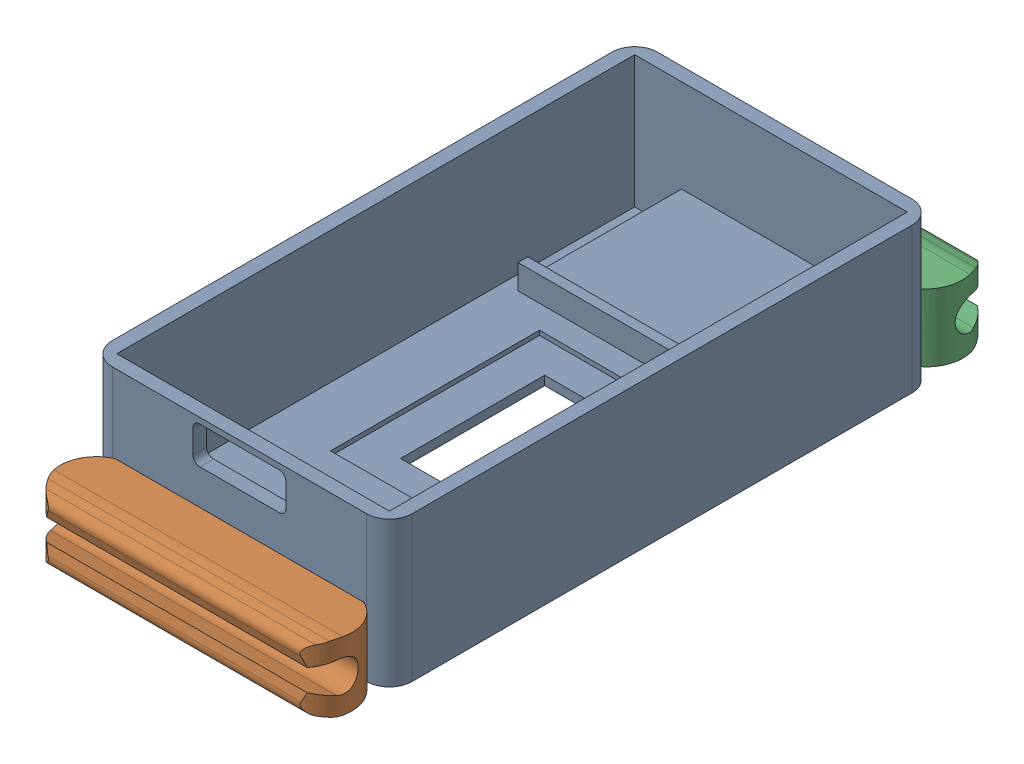
SolidWorks assembly Case Assembly, configuration Default. Lengths in mm.
Overall size (33 16 74.36).
8 component instances, 4 part files, 15 mates.
Components (placement in the parent):
- Case-1: Case [Default] at origin size (33 16 60)
- Apple Watch Band Female Connector-1: Apple Watch Band Female Connector [Default] at (16.9873 3.75 51.3416) x (0 0 -1) z (1 0 0) size (7.18 7.5 32)
- Apple Watch Band Female Connector-2: Apple Watch Band Female Connector [Default] at (16.9784 3.75 -13.864) x (0 0 1) z (-1 0 0) size (7.18 7.5 32)
- Case Top-1: Case Top [Default] at (0 16 -2.6495) (suppressed, hidden)
- Support Beam-2: Support Beam [Default] at (20.7334 64.9364 -6.6469) x (0.999394 0 -0.034819) z (0.034819 0 0.999394) (suppressed, hidden)
- Support Beam-5: Support Beam [Default] at (-3.0213 64.9364 -6.9302) (suppressed, hidden)
- Support Beam-7: Support Beam [Default] at (20.7744 64.9364 43.8698) (suppressed, hidden)
- Support Beam-8: Support Beam [Default] at (-3.0256 64.9364 43.8698) (suppressed, hidden)
Mates (geometry in assembly coordinates):
- Coincident1: coincident anti-aligned: line of Case-1 through (2.9896 0 48.7388) axis (1 0 0); line of Apple Watch Band Female Connector-1 through (30.6627 0 48.7388) axis (-1 0 0)
- Coincident2: coincident anti-aligned: plane of Case-1 through (0.4896 16 48.7388) normal (0 0 1); plane of Apple Watch Band Female Connector-1 through (32.9873 3.75 48.7388) normal (0 0 -1)
- Coincident3: coincident anti-aligned: line of Case-1 through (30.9896 0 -11.2612) axis (-1 0 0); line of Apple Watch Band Female Connector-2 through (3.303 0 -11.2612) axis (1 0 0)
- Coincident4: coincident anti-aligned: plane of Case-1 through (0.4896 16 -11.2612) normal (0 0 -1); plane of Apple Watch Band Female Connector-2 through (0.9784 3.75 -11.2612) normal (0 0 1)
- Width1: width anti-aligned: plane of Case Top-1 through (0.4896 17.27 -11.2612) normal (-1 0 0); plane of Case-1 through (33.4896 17.27 -11.2612) normal (1 0 0); plane of Case Top-1 through (33.4896 16 -11.2612) normal (1 0 0); plane of Case-1 through (0.4896 16 -11.2612) normal (-1 0 0)
- Width2: width anti-aligned: plane of Case Top-1 through (0.4896 17.27 -11.2612) normal (0 0 -1); plane of Case-1 through (0.4896 17.27 48.7388) normal (0 0 1); plane of Case Top-1 through (0.4896 16 48.7388) normal (0 0 1); plane of Case-1 through (0.4896 16 -11.2612) normal (0 0 -1)
- Coincident6: coincident anti-aligned: plane of Case-1 through (0 16 0) normal (0 1 0); plane of Case Top-1 through (0 16 -2.6495) normal (0 -1 0)
- Concentric3: concentric aligned: circle of Case Top-1; cylinder of Support Beam-2 through (28.8896 0 -5.6112) axis (0 1 0) radius 1.2457
- Coincident7: coincident aligned: plane of Case Top-1 through (0 17.27 -2.6495) normal (0 1 0); circle of Support Beam-2
- Concentric4: concentric aligned: cylinder of Case Top-1 through (5.0939 15.999 -5.6112) axis (0 1 0) radius 1.2457; cylinder of Support Beam-5 through (5.0939 0 -5.6112) axis (0 1 0) radius 1.1441
- Coincident9: coincident anti-aligned: plane of Case Top-1 through (0 17.27 -2.6495) normal (0 1 0); plane of Support Beam-5 through (5.0939 17.27 -5.6112) normal (0 -1 0)
- Concentric5: concentric aligned: cylinder of Case Top-1 through (28.8896 15.999 45.1888) axis (0 1 0) radius 1.25; cylinder of Support Beam-7 through (28.8896 0 45.1888) axis (0 1 0) radius 1.1441
- Coincident10: coincident anti-aligned: plane of Case Top-1 through (0 17.27 -2.6495) normal (0 1 0); plane of Support Beam-7 through (28.8896 17.27 45.1888) normal (0 -1 0)
- Concentric6: concentric aligned: cylinder of Case Top-1 through (5.0896 15.999 45.1888) axis (0 1 0) radius 1.25; cylinder of Support Beam-8 through (5.0896 0 45.1888) axis (0 1 0) radius 1.1441
- Coincident11: coincident anti-aligned: plane of Case Top-1 through (0 17.27 -2.6495) normal (0 1 0); plane of Support Beam-8 through (5.0896 17.27 45.1888) normal (0 -1 0)
